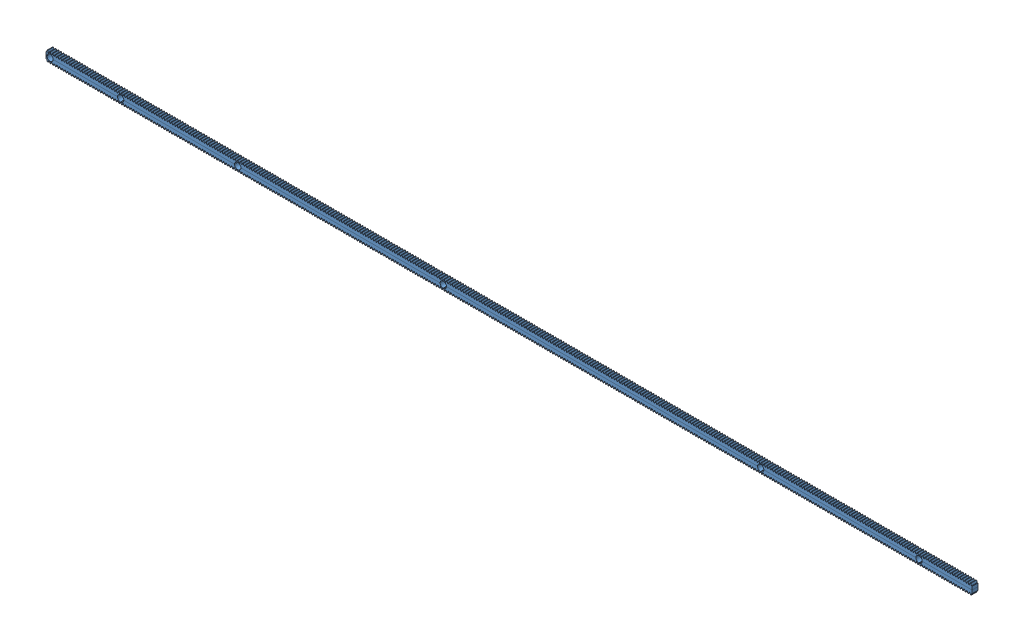
SolidWorks assembly RACK NEW, configuration Default. Lengths in mm.
Overall size (1100 12 7).
2 component instances, 1 part files, 3 mates.
Components (placement in the parent):
- rack spur rectangular_am-3: rack spur rectangular_am [Metric - Rack-spur - rectangular 1M 20PA 7FW 5PH 1100L---SAll] at (-723.2159 -44.4834 124.5487) size (1100 6 7)
- rack spur rectangular_am-4: rack spur rectangular_am [Metric - Rack-spur - rectangular 1M 20PA 7FW 5PH 1100L---SAll] at (376.7841 -44.4834 124.5487) x (-1 0 0) z (0 0 1) size (1100 6 7)
Mates (geometry in assembly coordinates):
- Coincident24: coincident anti-aligned: plane of rack spur rectangular_am-3 through (-723.2159 -44.4834 117.5487) normal (0 -1 0); plane of rack spur rectangular_am-4 through (376.7841 -44.4834 117.5487) normal (0 1 0)
- Coincident25: coincident aligned: plane of rack spur rectangular_am-3 through (-723.2159 -44.4834 117.5487) normal (-1 0 0); plane of rack spur rectangular_am-4 through (-723.2159 -44.4834 117.5487) normal (-1 0 0)
- Coincident26: coincident aligned: plane of rack spur rectangular_am-3 through (-723.2159 -38.4834 117.5487) normal (0 0 -1); plane of rack spur rectangular_am-4 through (376.7841 -50.4834 117.5487) normal (0 0 -1)
